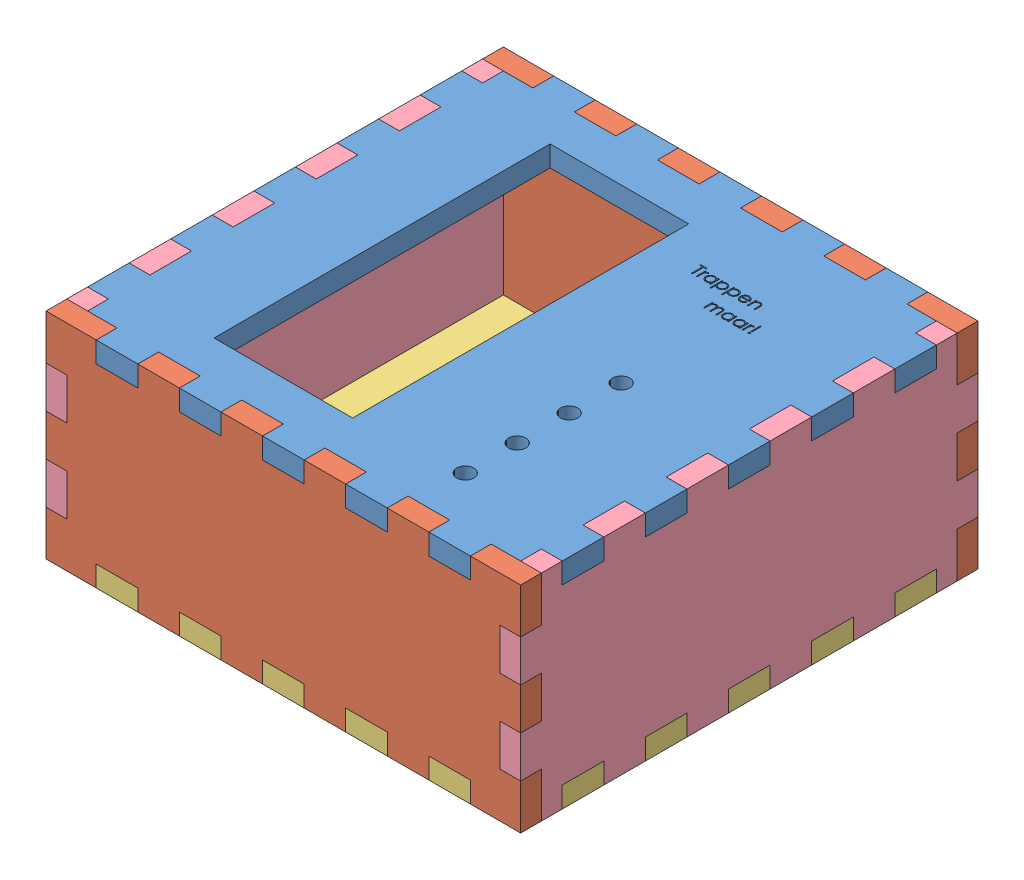
SolidWorks assembly BOX, configuration Default. Lengths in mm.
Overall size (137 62 132).
6 component instances, 4 part files, 15 mates.
Components (placement in the parent):
- bovenkant-1: bovenkant [Default] at (-140.9518 154.355 119.0853) size (137 6 132)
- korte zijkant-1: korte zijkant [Default] at (-140.9518 129.355 53.0853) x (-1 0 0) z (0 1 0) size (137 6 62)
- onderkant-1: onderkant [Default] at (-140.9518 98.355 119.0853) size (137 6 132)
- korte zijkant-2: korte zijkant [Default] at (-140.9518 129.355 179.0853) x (1 0 0) z (0 -1 0) size (137 6 62)
- lange zijkant-1: lange zijkant [Default] at (-78.4518 129.355 119.0853) x (0 0 -1) z (0 -1 0) size (132 6 62)
- lange zijkant-2: lange zijkant [Default] at (-209.4518 129.355 119.0853) x (0 0 -1) z (0 -1 0) size (132 6 62)
Mates (geometry in assembly coordinates):
- Coincident3: coincident anti-aligned: plane of onderkant-1 through (-110.9518 104.355 119.0853) normal (1 0 0); plane of korte zijkant-2 through (-110.9518 129.355 185.0853) normal (-1 0 0)
- Coincident5: coincident aligned: plane of onderkant-1 through (-140.9518 104.355 185.0853) normal (0 0 1); plane of korte zijkant-2 through (-140.9518 129.355 185.0853) normal (0 0 1)
- Coincident6: coincident aligned: plane of onderkant-1 through (-140.9518 98.355 119.0853) normal (0 -1 0); plane of korte zijkant-2 through (-140.9518 98.355 185.0853) normal (0 -1 0)
- Coincident7: coincident aligned: plane of bovenkant-1 through (-140.9518 160.355 119.0853) normal (0 1 0); plane of korte zijkant-2 through (-140.9518 160.355 185.0853) normal (0 1 0)
- Coincident8: coincident anti-aligned: plane of bovenkant-1 through (-86.9518 160.355 119.0853) normal (1 0 0); plane of korte zijkant-2 through (-86.9518 129.355 185.0853) normal (-1 0 0)
- Coincident9: coincident anti-aligned: plane of bovenkant-1 through (-140.9518 160.355 179.0853) normal (0 0 1); plane of korte zijkant-2 through (-140.9518 129.355 179.0853) normal (0 0 -1)
- Coincident10: coincident aligned: plane of bovenkant-1 through (-140.9518 160.355 53.0853) normal (0 0 -1); plane of korte zijkant-1 through (-140.9518 129.355 53.0853) normal (0 0 -1)
- Coincident11: coincident aligned: plane of korte zijkant-1 through (-140.9518 98.355 59.0853) normal (0 -1 0); plane of onderkant-1 through (-140.9518 98.355 119.0853) normal (0 -1 0)
- Coincident12: coincident anti-aligned: plane of korte zijkant-1 through (-194.9518 129.355 59.0853) normal (1 0 0); plane of onderkant-1 through (-194.9518 104.355 119.0853) normal (-1 0 0)
- Coincident16: coincident aligned: plane of korte zijkant-1 through (-140.9518 129.355 53.0853) normal (0 0 -1); plane of lange zijkant-1 through (-72.4518 129.355 53.0853) normal (0 0 -1)
- Coincident17: coincident aligned: plane of bovenkant-1 through (-140.9518 160.355 119.0853) normal (0 1 0); plane of lange zijkant-1 through (-72.4518 160.355 119.0853) normal (0 1 0)
- Coincident19: coincident anti-aligned: plane of bovenkant-1 through (-78.4518 160.355 119.0853) normal (1 0 0); plane of lange zijkant-1 through (-78.4518 129.355 119.0853) normal (-1 0 0)
- Coincident20: coincident anti-aligned: plane of bovenkant-1 through (-203.4518 160.355 119.0853) normal (-1 0 0); plane of lange zijkant-2 through (-203.4518 129.355 119.0853) normal (1 0 0)
- Coincident21: coincident anti-aligned: plane of korte zijkant-2 through (-140.9518 147.355 185.0853) normal (0 -1 0); plane of lange zijkant-2 through (-203.4518 147.355 119.0853) normal (0 1 0)
- Coincident22: coincident aligned: plane of korte zijkant-2 through (-140.9518 129.355 185.0853) normal (0 0 1); plane of lange zijkant-2 through (-203.4518 129.355 185.0853) normal (0 0 1)
